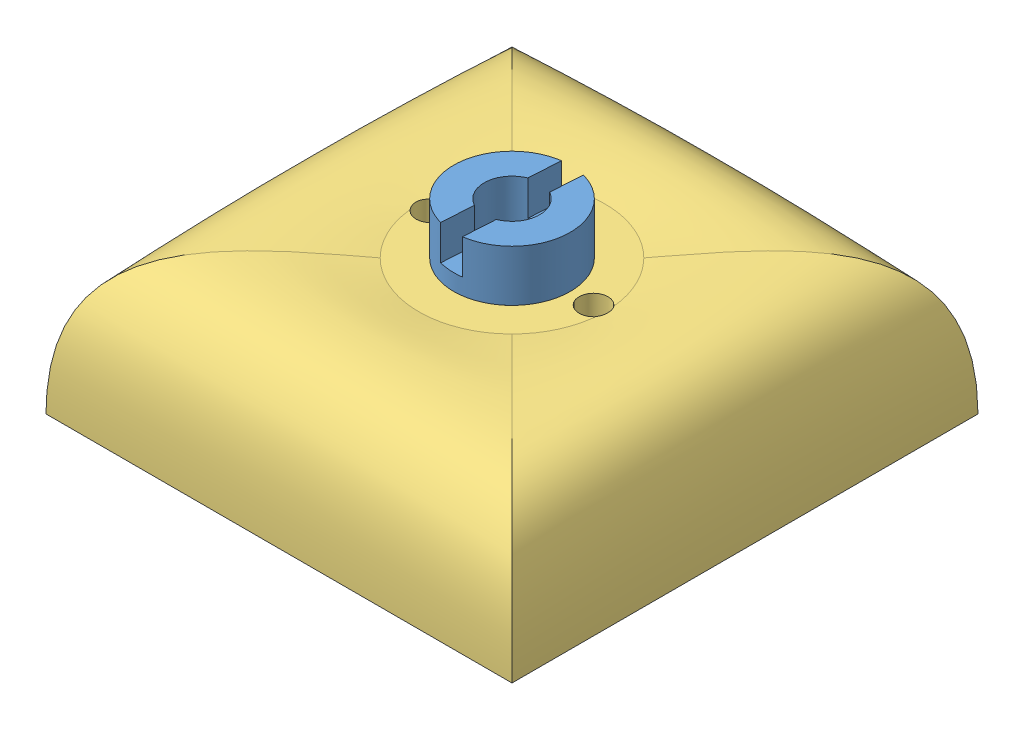
SolidWorks assembly ShuttleMoldAssembly, configuration Default. Lengths in mm.
Overall size (10.01 4 10.01).
7 component instances, 6 part files, 12 mates.
Components (placement in the parent):
- ShuttleMold-1: ShuttleMold [Default] at (4.512 2.6734 8.9938) size (10 3.17 10) (hidden)
- drive_threaded_rod_25mm-1: drive_threaded_rod_25mm [Default] at (4.512 2.6734 8.9938) size (1.64 25.22 1.64) (hidden)
- Grooved Nut-1: Grooved Nut [Default] at (4.512 5.8484 8.9938) x (0.060623 0 -0.998161) z (0.998161 0 0.060623) size (2.5 4 2.5)
- AcrylicMoldFill_1-1: AcrylicMoldFill_1 [Default] at (4.512 5.8484 8.9938) size (8 3.25 8)
- AcrylicMoldFill_2-1: AcrylicMoldFill_2 [Default] at (4.512 5.8484 8.9938) size (10.01 3.16 10.01)
- stabilizer_23g_25mm-1: stabilizer_23g_25mm [Default] at (6.262 2.6734 8.9938) size (0.62 25 0.62) (hidden)
- stabilizer_23g_25mm-2: stabilizer_23g_25mm [Default] at (2.762 2.6734 8.9938) size (0.62 25 0.62) (hidden)
Mates (geometry in assembly coordinates):
- Concentric2: concentric aligned: circle of ShuttleMold-1; circle of drive_threaded_rod_25mm-1
- Coincident3: coincident aligned: plane of ShuttleMold-1 through (4.512 2.6734 8.9938) normal (0 -1 0); plane of drive_threaded_rod_25mm-1 through (4.512 2.6734 8.9938) normal (0 -1 0)
- Concentric3: concentric anti-aligned: circle of drive_threaded_rod_25mm-1; circle of Grooved Nut-1
- Coincident4: coincident anti-aligned: plane of ShuttleMold-1 through (4.512 5.8484 8.9938) normal (0 1 0); plane of Grooved Nut-1 through (4.512 5.8484 8.9938) normal (0 -1 0)
- Coincident5: coincident anti-aligned: plane of ShuttleMold-1 through (4.512 5.8484 8.9938) normal (0 1 0); plane of AcrylicMoldFill_1-1 through (4.512 5.8484 8.9938) normal (0 -1 0)
- Concentric4: concentric aligned: circle of ShuttleMold-1; circle of AcrylicMoldFill_1-1
- Concentric5: concentric aligned: circle of ShuttleMold-1; circle of AcrylicMoldFill_2-1
- Coincident7: coincident anti-aligned: plane of ShuttleMold-1 through (4.512 5.8484 8.9938) normal (0 1 0); plane of AcrylicMoldFill_2-1 through (4.512 5.8484 8.9938) normal (0 -1 0)
- Concentric6: concentric aligned: circle of ShuttleMold-1; circle of stabilizer_23g_25mm-1
- Coincident8: coincident aligned: plane of ShuttleMold-1 through (4.512 2.6734 8.9938) normal (0 -1 0); plane of stabilizer_23g_25mm-1 through (6.262 2.6734 8.9938) normal (0 -1 0)
- Concentric7: concentric aligned: circle of ShuttleMold-1; circle of stabilizer_23g_25mm-2
- Coincident9: coincident aligned: plane of ShuttleMold-1 through (4.512 2.6734 8.9938) normal (0 -1 0); plane of stabilizer_23g_25mm-2 through (2.762 2.6734 8.9938) normal (0 -1 0)
